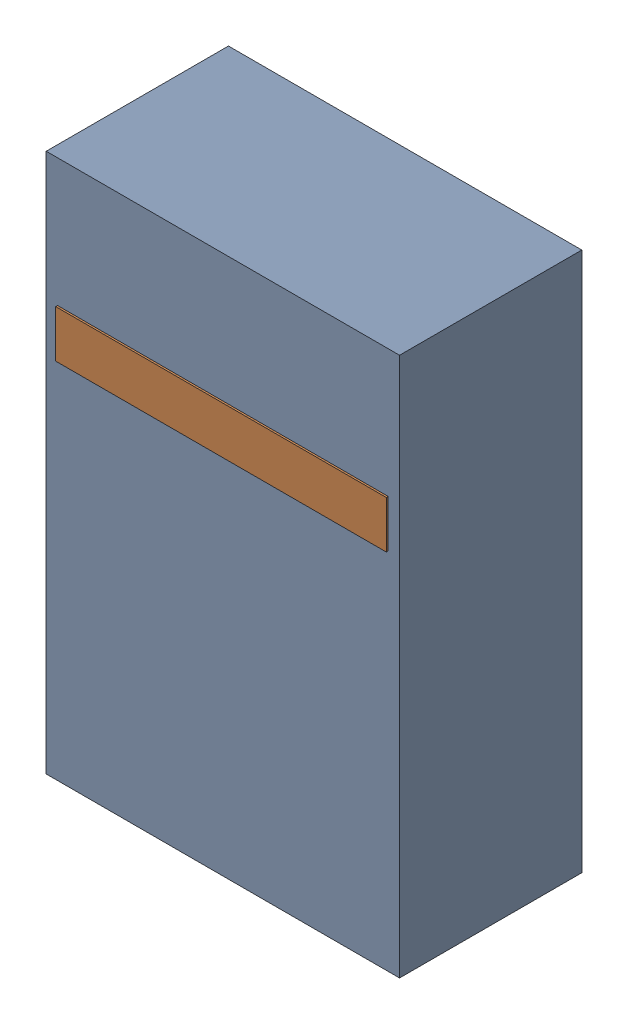
SolidWorks assembly D42, configuration Default. Lengths in mm.
Overall size (1.9 2.9 0.99).
4 component instances, 2 part files, 0 mates.
Components (placement in the parent):
- 1151710376-1: 1151710376 [Default] at (167.767 68.707 0) size (1.9 2.9 0.98)
  - Extruded-1: Extruded [Default] at origin size (1.9 2.9 0.98)
- 1151710512-1: 1151710512 [Default] at (167.767 69.342 0.95) size (1.78 0.25 0.04)
  - Extruded_1-1: Extruded_1 [Default] at origin size (1.78 0.25 0.04)
